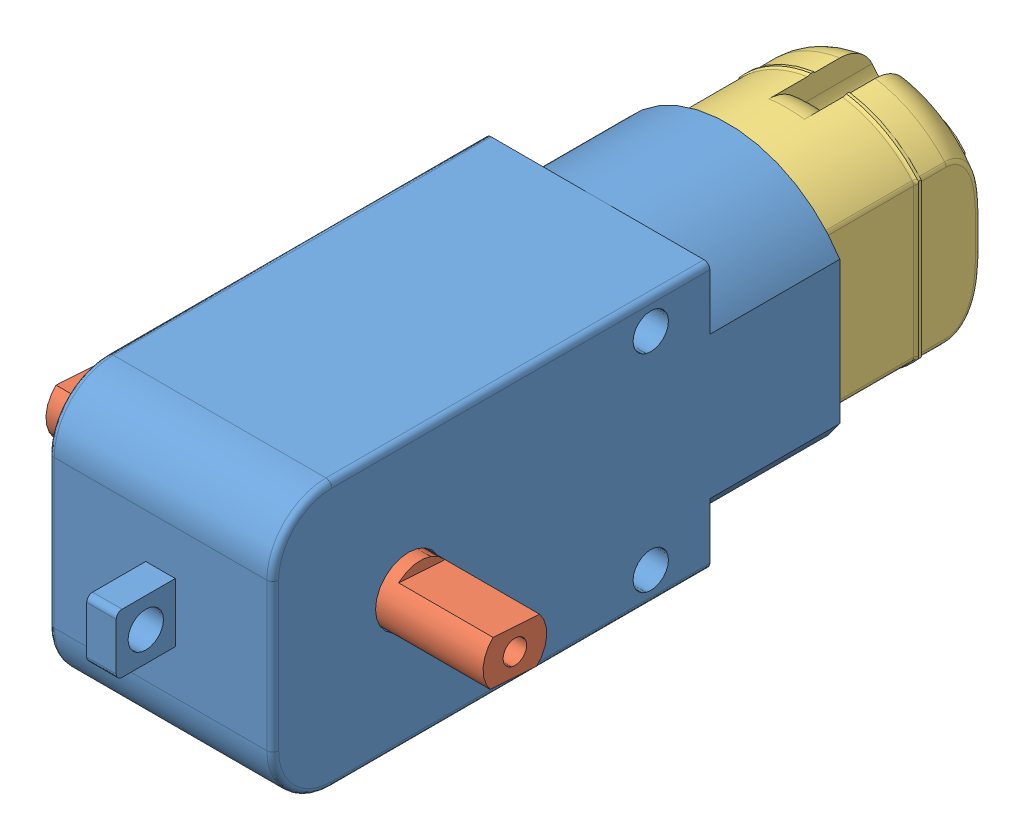
SolidWorks assembly DC Motor Gearbox, configuration Default. Lengths in mm.
Overall size (37 22.5 70).
3 component instances, 3 part files, 11 mates.
Components (placement in the parent):
- Gearbox-1: Gearbox [Default] at (19.5167 31.236 22.8921) size (19 22.5 53)
- output shaft-1: output shaft [Default] at (19.5167 31.236 48.3921) x (1 0 0) z (0 -0.997873 0.065186) size (37 5.4 5.4)
- motor-1: motor [Default] at (19.5167 31.236 -2.1079) size (17.2 19.92 37.8)
Mates (geometry in assembly coordinates):
- Concentric1: concentric anti-aligned: cylinder of Gearbox-1 through (10.0167 31.236 48.3921) axis (1 0 0) radius 2.8; cylinder of output shaft-1 through (38.0167 31.236 48.3921) axis (-1 0 0) radius 2.7
- Coincident2: coincident aligned: plane of Gearbox-1 through (19.5167 31.236 22.8921) normal (1 0 0); plane of output shaft-1 through (19.5167 31.236 48.3921) normal (1 0 0)
- Concentric2: concentric aligned: cylinder of Gearbox-1 through (19.5167 31.236 22.8921) axis (0 0 -1) radius 10.05; cylinder of motor-1 through (19.5167 31.236 22.8921) axis (0 0 -1) radius 9.9
- Parallel1: parallel anti-aligned: plane of Gearbox-1 through (27.8167 36.9028 22.8921) normal (-1 0 0); plane of motor-1 through (27.0167 37.6982 22.8921) normal (1 0 0)
- Coincident3: coincident anti-aligned: plane of Gearbox-1 through (19.5167 31.236 22.8921) normal (0 0 -1); plane of motor-1 through (19.5167 31.236 22.8921) normal (0 0 1)
- Concentric3: concentric anti-aligned: cylinder of output shaft-1 through (38.0167 31.236 48.3921) axis (-1 0 0) radius 2.7; cylinder of ? through (-0.6833 31.236 48.3921) axis (1 0 0) radius 3.25
- Coincident4: coincident anti-aligned: plane of output shaft-1 through (1.0167 31.236 48.3921) normal (-1 0 0); plane of ? through (1.0167 31.236 48.3921) normal (1 0 0)
- Parallel2: parallel aligned: plane of output shaft-1 through (9.0167 33.2103 50.234) normal (0 0.997873 -0.065186); plane of ? through (-0.6833 34.4651 48.7607) normal (0 -0.623012 -0.782212)
- Parallel3: parallel anti-aligned: plane of output shaft-1 through (30.0167 29.5182 50.4751) normal (0 -0.997873 0.065186); plane of ? through (30.0167 28.7912 46.2508) normal (0 0.997873 -0.065186)
- Concentric4: concentric anti-aligned: cylinder of output shaft-1 through (38.0167 31.236 48.3921) axis (-1 0 0) radius 2.7; cylinder of ? through (30.0167 31.236 48.3921) axis (1 0 0) radius 3.25
- Coincident7: coincident anti-aligned: plane of output shaft-1 through (38.0167 31.236 48.3921) normal (1 0 0); plane of ? through (38.0167 31.236 48.3921) normal (-1 0 0)
